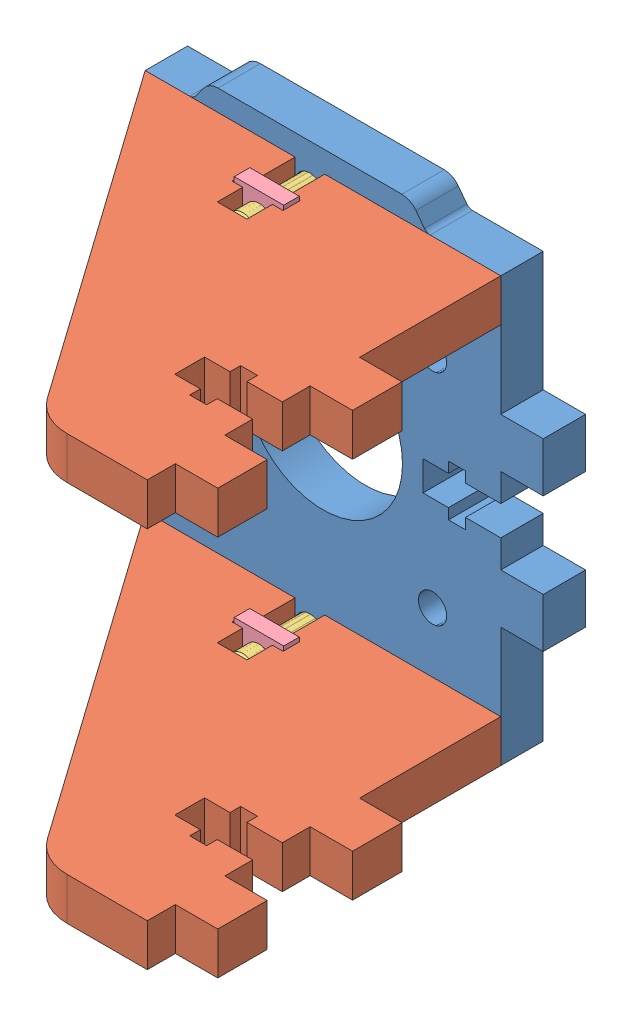
SolidWorks assembly nema17_mount_axis_z, configuration По умолчанию. Lengths in mm.
Overall size (56.3 87.12 58.96).
7 component instances, 4 part files, 20 mates.
Components (placement in the parent):
- Деталь2^nema17_mount_axis_z-1: Деталь2^nema17_mount_axis_z [По умолчанию] at origin size (56.3 66 6) (virtual)
- Деталь3^nema17_mount_axis_z-1: Деталь3^nema17_mount_axis_z [По умолчанию] at (0 30 0) x (1 0 0) z (0 1 0) size (56.3 56 6) (virtual)
- Деталь3^nema17_mount_axis_z-2: Деталь3^nema17_mount_axis_z [По умолчанию] at (0 -24 0) x (1 0 0) z (0 1 0) size (56.3 56 6) (virtual)
- DIN967-5: DIN967 [M4х16] at (-1.8501 27 -3.05) x (0 0 1) z (0 1 0) size (18.96 34 34.42)
- din 562 m4-5: din 562 m4 [По умолчанию] at (-1.8503 26.9982 11) size (7 7 2.2)
- DIN967-6: DIN967 [M4х16] at (-1.8501 -27 -3.05) x (0 0 1) z (0 -1 0) size (18.96 34 34.42)
- din 562 m4-6: din 562 m4 [По умолчанию] at (-1.85 -26.9982 11) x (-1 0 0) z (0 0 1) size (7 7 2.2)
Mates (geometry in assembly coordinates):
- На месте1: in place: plane of Деталь2^nema17_mount_axis_z-1 through (0 0 0) normal (0 0 1); moOrthogonalPlaneRef_w of Деталь2^nema17_mount_axis_z-1 through (0 0 0) normal (0 1 0); plane of Деталь2^nema17_mount_axis_z-1 through (0 0 0) normal (1 0 0); unknown of Деталь2^nema17_mount_axis_z-1
- Совпадение1: coincident aligned: 
- Совпадение2: coincident aligned: plane of Деталь2^nema17_mount_axis_z-1 through (0 0 0) normal (0 1 0)
- Совпадение3: coincident anti-aligned: plane of Деталь2^nema17_mount_axis_z-1 through (0 0 0) normal (1 0 0)
- На месте2: in place: plane of Деталь2^nema17_mount_axis_z-1 through (-24.2298 28.9024 6) normal (0 1 0); plane of ? through (0 28.9024 0) normal (0 1 0); plane of Деталь2^nema17_mount_axis_z-1 through (-24.2298 28.9024 6) normal (0 1 0); plane of ? through (0 28.9024 0) normal (0 0 -1); plane of Деталь2^nema17_mount_axis_z-1 through (-24.2298 28.9024 6) normal (0 1 0); plane of ? through (0 28.9024 0) normal (1 0 0); plane of Деталь2^nema17_mount_axis_z-1 through (-25.1499 30 6) normal (0 1 0); unknown of Деталь3^nema17_mount_axis_z-1
- Совпадение4: coincident aligned: plane of Деталь2^nema17_mount_axis_z-1; plane of Деталь3^nema17_mount_axis_z-1
- Совпадение5: coincident aligned: moOrthogonalPlaneRef_w of Деталь2^nema17_mount_axis_z-1 through (0 30 0) normal (0 0 -1); plane of Деталь3^nema17_mount_axis_z-1 through (0 30 0) normal (0 0 -1)
- Совпадение6: coincident anti-aligned: moOrthogonalPlaneRef_w of Деталь2^nema17_mount_axis_z-1 through (0 30 0) normal (-1 0 0); plane of Деталь3^nema17_mount_axis_z-1 through (0 30 0) normal (1 0 0)
- Совпадение6: coincident aligned: plane of Деталь2^nema17_mount_axis_z-1 through (-25.1499 -30 6) normal (0 -1 0); plane of Деталь3^nema17_mount_axis_z-2 through (13.7766 -30 49) normal (0 -1 0)
- Совпадение10: coincident aligned: plane of Деталь2^nema17_mount_axis_z-1 through (25.1499 -30 6) normal (1 0 0); plane of Деталь3^nema17_mount_axis_z-2 through (25.1499 -30 6) normal (1 0 0)
- Совпадение18: coincident anti-aligned: plane of Деталь2^nema17_mount_axis_z-1 through (0 0 0) normal (0 0 -1); plane of DIN967-5 through (0.1499 27 0) normal (0 0 1)
- Совпадение19: coincident anti-aligned: plane of Деталь2^nema17_mount_axis_z-1 through (-25.1499 30 6) normal (0 1 0); plane of DIN967-5 through (-1.8501 30 -3.05) normal (0 -1 0)
- Расстояние6: distance = 10 mm anti-aligned: plane of DIN967-5 through (15.1499 27 -3.05) normal (-1 0 0); plane of Деталь2^nema17_mount_axis_z-1 through (25.1499 -30 6) normal (1 0 0)
- Концентричный10: concentric anti-aligned: cylinder of DIN967-5 through (-1.8501 27 -9.4) axis (0 0 -1) radius 2; cylinder of din 562 m4-5 through (-1.8501 27 11) axis (0 0 1) radius 2
- Совпадение21: coincident anti-aligned: plane of din 562 m4-5 through (-1.8503 26.9982 11) normal (0 0 -1); plane of Деталь3^nema17_mount_axis_z-1 through (-3.9501 24 11) normal (0 0 1)
- Совпадение22: coincident anti-aligned: plane of Деталь2^nema17_mount_axis_z-1 through (-25.1499 -30 6) normal (0 -1 0); plane of DIN967-6 through (-1.8501 -30 -3.05) normal (0 1 0)
- Совпадение23: coincident anti-aligned: plane of Деталь2^nema17_mount_axis_z-1 through (0 0 0) normal (0 0 -1); plane of DIN967-6 through (-3.8501 -27 0) normal (0 0 1)
- Совпадение24: coincident anti-aligned: plane of Деталь2^nema17_mount_axis_z-1 through (-25.1499 -30 6) normal (0 -1 0); plane of DIN967-6 through (-1.8501 -30 -3.05) normal (0 1 0)
- Расстояние7: distance = 10 mm anti-aligned: plane of DIN967-6 through (15.1499 -27 -3.05) normal (-1 0 0); plane of Деталь2^nema17_mount_axis_z-1 through (25.1499 -30 6) normal (1 0 0)
- Концентричный12: concentric anti-aligned: cylinder of DIN967-6 through (-1.8501 -27 -9.4) axis (0 0 -1) radius 2; cylinder of din 562 m4-6 through (-1.8501 -27 11) axis (0 0 1) radius 2
